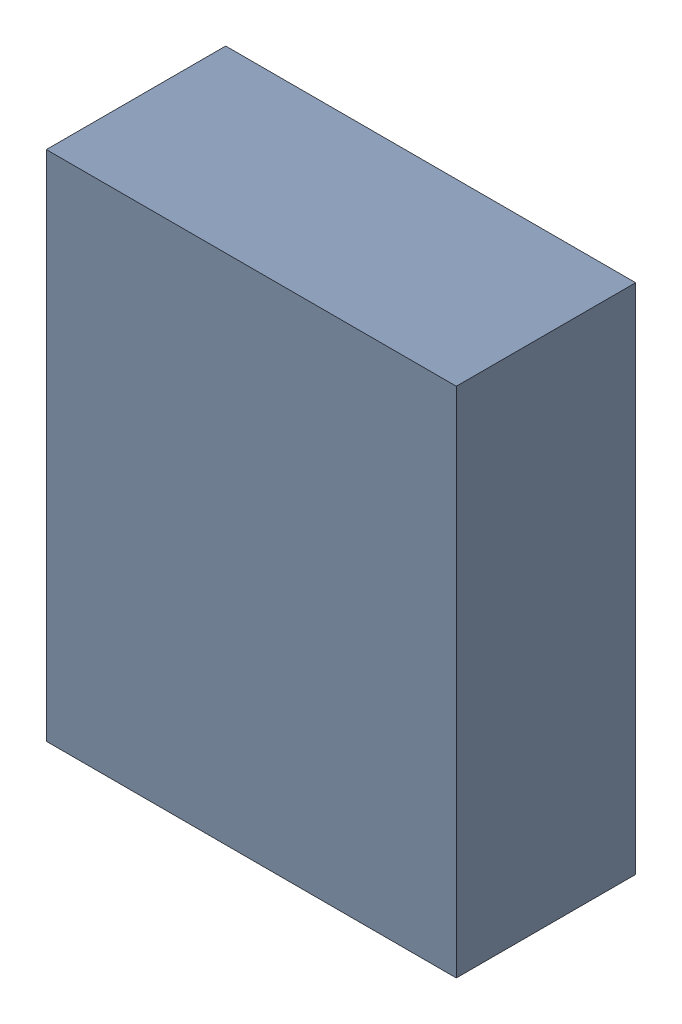
SolidWorks assembly Q1_1, configuration Default. Lengths in mm.
Overall size (4 5 1.75).
2 component instances, 1 part files, 0 mates.
Components (placement in the parent):
- 76846376-1: 76846376 [Default] at (7.0866 26.0858 -2.1615) size (4 5 1.75)
  - Extruded-1: Extruded [Default] at origin size (4 5 1.75)
